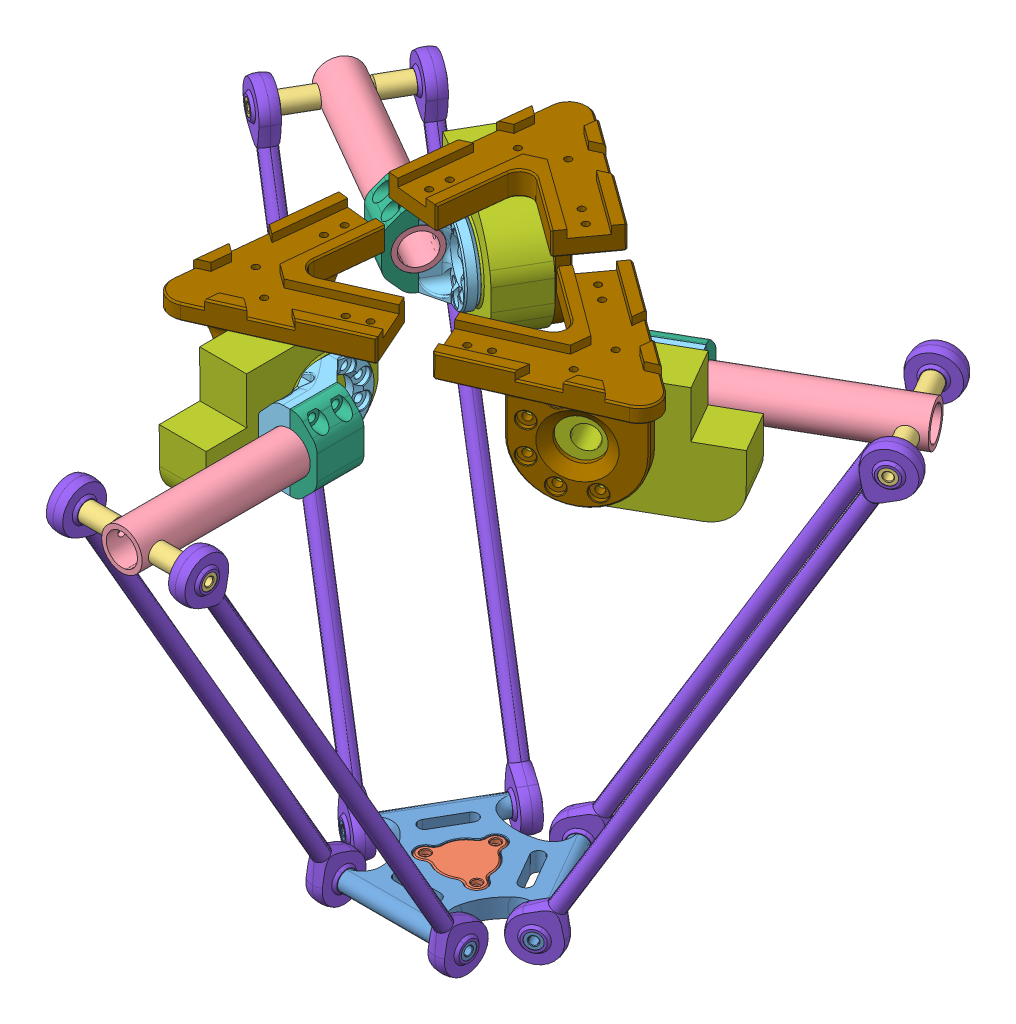
SolidWorks assembly delta-unattached-static, configuration Default. Lengths in mm.
Overall size (445.41 366.22 385.74).
29 component instances, 9 part files, 69 mates.
Components (placement in the parent):
- flange-star-1: flange-star [Default] at origin size (130.67 31.15 114.22)
- calibration-pin-1: calibration-pin [Default] at (0 12 0) x (0.5 0 -0.866025) z (-0.866025 0 -0.5) size (44.16 32 40.5)
- connection-tap-joint-2: connection-tap-joint [Default] at (-45.9 293.4704 210.0514) x (0 -1 0) z (0 0 1) size (12 32.9 12)
- connection-tap-joint-3: connection-tap-joint [Default] at (45.9 293.4704 210.0514) x (0 0.993683 -0.11222) z (0 0.11222 0.993683) size (12 32.9 12)
- proximal-link-1: proximal-link [Default] at (0 293.4704 82.5514) x (0 -1 0) z (0 0 1) size (26 26 137.5)
- revolute-joint-1: revolute-joint [Default] at (-20 293.4704 70.0514) x (0 0 1) z (0 1 0) size (66.5 20.7 48.61)
- joint-clamp-1: joint-clamp [Default] at (8.55 293.4829 82.5514) x (0 -1 0) z (0 0 1) size (48 17.3 30)
- connection-tap-joint-4: connection-tap-joint [Default] at (-158.9598 293.4704 -144.7763) x (-0.224339 0.965866 -0.129522) z (0.836464 0.259044 0.482933) size (12 32.9 12)
- connection-tap-joint-5: connection-tap-joint [Default] at (-204.8598 293.4704 -65.2751) x (0.186633 -0.976503 0.107752) z (0.845676 0.215505 0.488251) size (12 32.9 12)
- proximal-link-3: proximal-link [Default] at (-71.4916 293.4704 -41.2757) x (0 -1 0) z (-0.866025 0 -0.5) size (26 26 137.5)
- revolute-joint-2: revolute-joint [Default] at (-50.6663 293.4704 -52.3462) x (-0.866025 0 -0.5) z (0 1 0) size (66.5 20.7 48.61)
- joint-clamp-2: joint-clamp [Default] at (-75.7666 293.4829 -33.8712) x (0 -1 0) z (-0.866025 0 -0.5) size (48 17.3 30)
- connection-tap-joint-6: connection-tap-joint [Default] at (204.8598 293.4704 -65.2751) x (0.224339 0.965866 -0.129522) z (-0.836464 0.259044 0.482933) size (12 32.9 12)
- connection-tap-joint-7: connection-tap-joint [Default] at (158.9598 293.4704 -144.7763) x (-0.424943 0.871339 0.245341) z (0.754601 0.490682 -0.435669) size (12 32.9 12)
- proximal-link-5: proximal-link [Default] at (71.4916 293.4704 -41.2757) x (0 -1 0) z (0.866025 0 -0.5) size (26 26 137.5)
- revolute-joint-3: revolute-joint [Default] at (70.6663 293.4704 -17.7052) x (0.866025 0 -0.5) z (0 1 0) size (66.5 20.7 48.61)
- joint-clamp-3: joint-clamp [Default] at (67.2166 293.4829 -48.6802) x (0 -1 0) z (0.866025 0 -0.5) size (48 17.3 30)
- Hebi-X5-1_draft-3: Hebi-X5-1_draft [Default] at (-51.1 293.3938 90.0512) x (0 -0.999993 -0.003829) z (0 -0.003829 0.999993) size (73 31.1 110)
- KDGM_10_A_ER_J_2.stp-1: KDGM_10_A_ER_J_2.stp [Default] at (39.1 149.7122 127.048) x (0 0.500021 -0.866014) z (0 0.866014 0.500021) size (30 14 362)
- KDGM_10_A_ER_J_2.stp-2: KDGM_10_A_ER_J_2.stp [Default] at (-39.1 149.7122 127.048) x (0 0.500021 -0.866014) z (0 0.866014 0.500021) size (30 14 362)
- KDGM_10_A_ER_J_2.stp-3: KDGM_10_A_ER_J_2.stp [Default] at (-129.5768 149.7122 -29.6624) x (-0.74999 -0.500021 -0.433007) z (-0.43303 0.866014 -0.25001) size (30 14 362)
- KDGM_10_A_ER_J_2.stp-4: KDGM_10_A_ER_J_2.stp [Default] at (-90.4768 149.7122 -97.3856) x (-0.74999 -0.500021 -0.433007) z (-0.43303 0.866014 -0.25001) size (30 14 362)
- KDGM_10_A_ER_J_2.stp-5: KDGM_10_A_ER_J_2.stp [Default] at (90.4768 149.7122 -97.3856) x (-0.74999 0.500021 0.433007) z (0.43303 0.866014 -0.25001) size (30 14 362)
- KDGM_10_A_ER_J_2.stp-6: KDGM_10_A_ER_J_2.stp [Default] at (129.5768 149.7122 -29.6624) x (-0.74999 0.500021 0.433007) z (0.43303 0.866014 -0.25001) size (30 14 362)
- Hebi-X5-1_draft-4: Hebi-X5-1_draft [Default] at (103.5367 293.3938 -0.7717) x (-0.003316 -0.999993 0.001915) z (0.866019 -0.003829 -0.499996) size (73 31.1 110)
- Hebi-X5-1_draft-5: Hebi-X5-1_draft [Default] at (-52.4367 293.3938 -89.2795) x (0.003316 -0.999993 0.001915) z (-0.866019 -0.003829 -0.499996) size (73 31.1 110)
- base-mount-1: base-mount [Default] at (-51.1 293.4781 68.0514) x (0 -0.003829 0.999993) z (0 -0.999993 -0.003829) size (108.14 103.78 86.5)
- base-mount-2: base-mount [Default] at (84.4842 293.4781 10.2282) x (0.866019 -0.003829 -0.499996) z (-0.003316 -0.999993 0.001915) size (108.14 103.78 86.5)
- base-mount-3: base-mount [Default] at (-33.3842 293.4781 -78.2796) x (-0.866019 -0.003829 -0.499996) z (0.003316 -0.999993 0.001915) size (108.14 103.78 86.5)
Mates (geometry in assembly coordinates):
- Coincident1: coincident: plane of flange-star-1 through (-5.419 7 -18.5519) normal (0 1 0); plane of calibration-pin-1 through (10.4372 7 -0.081) normal (0 -1 0)
- Concentric1: concentric: cylinder of flange-star-1 through (0 21.5681 -19) axis (0 -1 0) radius 1.625; cylinder of calibration-pin-1 through (0 7 -19) axis (0 1 0) radius 1.625
- Concentric7: concentric: cylinder of connection-tap-joint-2 through (-13 293.4704 210.0514) axis (-1 0 0) radius 2.625; cylinder of proximal-link-1 through (150 293.4704 210.0514) axis (-1 0 0) radius 2.65
- Tangent4: tangent: plane of connection-tap-joint-2 through (-13 293.4704 210.0514) normal (1 0 0); cylinder of proximal-link-1 through (0 293.4704 220.0514) axis (0 0 -1) radius 13
- Concentric9: concentric: cylinder of connection-tap-joint-3 through (13 293.4704 210.0514) axis (1 0 0) radius 2.625; cylinder of proximal-link-1 through (150 293.4704 210.0514) axis (-1 0 0) radius 2.65
- Concentric10: concentric: cylinder of proximal-link-1 through (-13 293.4704 92.5514) axis (1 0 0) radius 2.5; cylinder of revolute-joint-1 through (-10.41 293.4704 92.5514) axis (-1 0 0) radius 2.45
- Concentric11: concentric: cylinder of proximal-link-1 through (0 293.4704 220.0514) axis (0 0 -1) radius 13; cylinder of revolute-joint-1 through (0 293.4704 112.5514) axis (0 0 -1) radius 13.125
- Concentric12: concentric: cylinder of revolute-joint-1 through (-20.6235 312.0454 105.0514) axis (1 0 0) radius 2.625; cylinder of joint-clamp-1 through (17.3 312.0454 105.0514) axis (-1 0 0) radius 2.625
- Concentric13: concentric: cylinder of revolute-joint-1 through (-20.6235 312.0454 90.0514) axis (1 0 0) radius 2.625; cylinder of joint-clamp-1 through (17.3 312.0454 90.0514) axis (-1 0 0) radius 2.625
- Coincident8: coincident: plane of revolute-joint-1 through (0 293.4704 70.0514) normal (1 0 0); plane of joint-clamp-1 through (0 293.4829 82.5514) normal (-1 0 0)
- Concentric14: concentric: cylinder of flange-star-1 through (-16.4545 21.5681 9.5) axis (0 -1 0) radius 1.625; cylinder of calibration-pin-1 through (-16.4545 7 9.5) axis (0 1 0) radius 1.625
- Concentric21: concentric: cylinder of connection-tap-joint-4 through (-175.4098 293.4704 -116.284) axis (0.5 0 -0.866025) radius 2.625; cylinder of proximal-link-3 through (-256.9098 293.4704 24.8781) axis (0.5 0 -0.866025) radius 2.65
- Tangent6: tangent: plane of connection-tap-joint-4 through (-175.4098 293.4704 -116.284) normal (-0.5 0 0.866025); cylinder of proximal-link-3 through (-190.5701 293.4704 -110.0257) axis (0.866025 0 0.5) radius 13
- Concentric22: concentric: cylinder of connection-tap-joint-5 through (-188.4098 293.4704 -93.7674) axis (-0.5 0 0.866025) radius 2.625; cylinder of proximal-link-3 through (-256.9098 293.4704 24.8781) axis (0.5 0 -0.866025) radius 2.65
- Concentric23: concentric: cylinder of proximal-link-3 through (-82.3121 293.4704 -62.534) axis (-0.5 0 0.866025) radius 2.5; cylinder of revolute-joint-2 through (-83.6071 293.4704 -60.291) axis (0.5 0 -0.866025) radius 2.45
- Concentric24: concentric: cylinder of proximal-link-3 through (-190.5701 293.4704 -110.0257) axis (0.866025 0 0.5) radius 13; cylinder of revolute-joint-2 through (-97.4724 293.4704 -56.2757) axis (0.866025 0 0.5) radius 13.125
- Concentric26: concentric: cylinder of revolute-joint-2 through (-67.6751 312.0454 -62.8862) axis (-0.5 0 0.866025) radius 2.625; cylinder of joint-clamp-2 through (-86.6368 312.0454 -30.0435) axis (0.5 0 -0.866025) radius 2.625
- Concentric27: concentric: cylinder of revolute-joint-2 through (-80.6654 312.0454 -70.3862) axis (-0.5 0 0.866025) radius 2.625; cylinder of joint-clamp-2 through (-99.6272 312.0454 -37.5435) axis (0.5 0 -0.866025) radius 2.625
- Coincident13: coincident: plane of revolute-joint-2 through (-60.6663 293.4704 -35.0257) normal (-0.5 0 0.866025); plane of joint-clamp-2 through (-71.4916 293.4829 -41.2757) normal (0.5 0 -0.866025)
- Concentric34: concentric: cylinder of connection-tap-joint-6 through (188.4098 293.4704 -93.7674) axis (0.5 0 0.866025) radius 2.625; cylinder of proximal-link-5 through (106.9098 293.4704 -234.9295) axis (0.5 0 0.866025) radius 2.65
- Tangent8: tangent: plane of connection-tap-joint-6 through (188.4098 293.4704 -93.7674) normal (-0.5 0 -0.866025); cylinder of proximal-link-5 through (190.5701 293.4704 -110.0257) axis (-0.866025 0 0.5) radius 13
- Concentric35: concentric: cylinder of connection-tap-joint-7 through (175.4098 293.4704 -116.284) axis (-0.5 0 -0.866025) radius 2.625; cylinder of proximal-link-5 through (106.9098 293.4704 -234.9295) axis (0.5 0 0.866025) radius 2.65
- Concentric36: concentric: cylinder of proximal-link-5 through (95.3121 293.4704 -40.0174) axis (-0.5 0 -0.866025) radius 2.5; cylinder of revolute-joint-3 through (94.0171 293.4704 -42.2604) axis (0.5 0 0.866025) radius 2.45
- Concentric37: concentric: cylinder of proximal-link-5 through (190.5701 293.4704 -110.0257) axis (-0.866025 0 0.5) radius 13; cylinder of revolute-joint-3 through (97.4724 293.4704 -56.2757) axis (-0.866025 0 0.5) radius 13.125
- Concentric38: concentric: cylinder of revolute-joint-3 through (88.2985 312.0454 -27.1652) axis (-0.5 0 -0.866025) radius 2.625; cylinder of joint-clamp-3 through (69.3368 312.0454 -60.0079) axis (0.5 0 0.866025) radius 2.625
- Concentric39: concentric: cylinder of revolute-joint-3 through (101.2889 312.0454 -34.6652) axis (-0.5 0 -0.866025) radius 2.625; cylinder of joint-clamp-3 through (82.3272 312.0454 -67.5079) axis (0.5 0 0.866025) radius 2.625
- Coincident19: coincident: plane of revolute-joint-3 through (60.6663 293.4704 -35.0257) normal (-0.5 0 -0.866025); plane of joint-clamp-3 through (71.4916 293.4829 -41.2757) normal (0.5 0 0.866025)
- Coincident22: coincident: plane of revolute-joint-1 through (-20 293.4704 70.0514) normal (-1 0 0); plane of Hebi-X5-1_draft-3 through (-20 293.4704 70.0514) normal (1 0 0)
- Concentric47: concentric: cylinder of flange-star-1 through (45.9 5.9539 44.0446) axis (-1 0 0) radius 4.9; cylinder of KDGM_10_A_ER_J_2.stp-1 through (39.1 5.9539 44.0446) axis (1 0 0) radius 5
- Coincident23: coincident: plane of flange-star-1 through (32.1 6 44) normal (1 0 0); plane of KDGM_10_A_ER_J_2.stp-1 through (32.1 5.9539 44.0446) normal (-1 0 0)
- Concentric48: concentric: cylinder of flange-star-1 through (-45.9 5.9539 44.0446) axis (1 0 0) radius 4.9; cylinder of KDGM_10_A_ER_J_2.stp-2 through (-39.1 5.9539 44.0446) axis (1 0 0) radius 5
- Coincident24: coincident: plane of flange-star-1 through (-32.1 6 44) normal (-1 0 0); plane of KDGM_10_A_ER_J_2.stp-2 through (-32.1 5.9539 44.0446) normal (1 0 0)
- Concentric49: concentric: cylinder of connection-tap-joint-2 through (-32.1 293.4704 210.0514) axis (-1 0 0) radius 4.9; cylinder of KDGM_10_A_ER_J_2.stp-2 through (-39.1 293.4704 210.0514) axis (-1 0 0) radius 5
- Tangent9: tangent: plane of connection-tap-joint-3 through (13 293.4704 210.0514) normal (-1 0 0); cylinder of proximal-link-1 through (0 293.4704 220.0514) axis (0 0 -1) radius 13
- Concentric50: concentric: cylinder of connection-tap-joint-3 through (32.1 293.4704 210.0514) axis (1 0 0) radius 4.9; cylinder of KDGM_10_A_ER_J_2.stp-1 through (39.1 293.4704 210.0514) axis (-1 0 0) radius 5
- Coincident25: coincident: plane of connection-tap-joint-2 through (-32.1 293.4704 210.0514) normal (-1 0 0); plane of KDGM_10_A_ER_J_2.stp-2 through (-32.1 293.4704 210.0514) normal (1 0 0)
- Concentric51: concentric: cylinder of connection-tap-joint-5 through (-197.9598 293.4704 -77.2263) axis (-0.5 0 0.866025) radius 4.9; cylinder of KDGM_10_A_ER_J_2.stp-3 through (-201.4598 293.4704 -71.1641) axis (-0.5 0 0.866025) radius 5
- Tangent10: tangent: plane of connection-tap-joint-5 through (-188.4098 293.4704 -93.7674) normal (0.5 0 -0.866025); cylinder of proximal-link-3 through (-190.5701 293.4704 -110.0257) axis (0.866025 0 0.5) radius 13
- Coincident26: coincident: plane of connection-tap-joint-5 through (-197.9598 293.4704 -77.2263) normal (-0.5 0 0.866025); plane of KDGM_10_A_ER_J_2.stp-3 through (-197.9598 293.4704 -77.2263) normal (0.5 0 -0.866025)
- Concentric52: concentric: cylinder of flange-star-1 through (-61.0937 5.9539 17.7283) axis (0.5 0 -0.866025) radius 4.9; cylinder of KDGM_10_A_ER_J_2.stp-3 through (-57.6937 5.9539 11.8393) axis (0.5 0 -0.866025) radius 5
- Coincident27: coincident: plane of flange-star-1 through (-54.1551 6 5.7994) normal (-0.5 0 0.866025); plane of KDGM_10_A_ER_J_2.stp-3 through (-54.1937 5.9539 5.7771) normal (0.5 0 -0.866025)
- Concentric53: concentric: cylinder of flange-star-1 through (-15.1937 5.9539 -61.7729) axis (-0.5 0 0.866025) radius 4.9; cylinder of KDGM_10_A_ER_J_2.stp-4 through (-18.5937 5.9539 -55.8839) axis (0.5 0 -0.866025) radius 5
- Concentric54: concentric: cylinder of connection-tap-joint-4 through (-165.8598 293.4704 -132.8251) axis (0.5 0 -0.866025) radius 4.9; cylinder of KDGM_10_A_ER_J_2.stp-4 through (-162.3598 293.4704 -138.8873) axis (-0.5 0 0.866025) radius 5
- Coincident28: coincident: plane of flange-star-1 through (-22.0551 6 -49.7994) normal (0.5 0 -0.866025); plane of KDGM_10_A_ER_J_2.stp-4 through (-22.0937 5.9539 -49.8217) normal (-0.5 0 0.866025)
- Concentric55: concentric: cylinder of connection-tap-joint-7 through (165.8598 293.4704 -132.8251) axis (-0.5 0 -0.866025) radius 4.9; cylinder of KDGM_10_A_ER_J_2.stp-5 through (162.3598 293.4704 -138.8873) axis (0.5 0 0.866025) radius 5
- Concentric56: concentric: cylinder of flange-star-1 through (15.1937 5.9539 -61.7729) axis (0.5 0 0.866025) radius 4.9; cylinder of KDGM_10_A_ER_J_2.stp-5 through (18.5937 5.9539 -55.8839) axis (-0.5 0 -0.866025) radius 5
- Coincident29: coincident: plane of flange-star-1 through (22.0551 6 -49.7994) normal (-0.5 0 -0.866025); plane of KDGM_10_A_ER_J_2.stp-5 through (22.0937 5.9539 -49.8217) normal (0.5 0 0.866025)
- Tangent11: tangent: plane of connection-tap-joint-7 through (175.4098 293.4704 -116.284) normal (0.5 0 0.866025); cylinder of proximal-link-5 through (190.5701 293.4704 -110.0257) axis (-0.866025 0 0.5) radius 13
- Concentric57: concentric: cylinder of connection-tap-joint-6 through (197.9598 293.4704 -77.2263) axis (0.5 0 0.866025) radius 4.9; cylinder of KDGM_10_A_ER_J_2.stp-6 through (201.4598 293.4704 -71.1641) axis (0.5 0 0.866025) radius 5
- Concentric58: concentric: cylinder of flange-star-1 through (61.0937 5.9539 17.7283) axis (-0.5 0 -0.866025) radius 4.9; cylinder of KDGM_10_A_ER_J_2.stp-6 through (57.6937 5.9539 11.8393) axis (-0.5 0 -0.866025) radius 5
- Coincident30: coincident: plane of flange-star-1 through (54.1551 6 5.7994) normal (0.5 0 0.866025); plane of KDGM_10_A_ER_J_2.stp-6 through (54.1937 5.9539 5.7771) normal (-0.5 0 -0.866025)
- Coincident31: coincident: plane of connection-tap-joint-6 through (197.9598 293.4704 -77.2263) normal (0.5 0 0.866025); plane of KDGM_10_A_ER_J_2.stp-6 through (197.9598 293.4704 -77.2263) normal (-0.5 0 -0.866025)
- Coincident47: coincident: plane of proximal-link-5 through (71.4916 293.4704 -41.2757) normal (0 -1 0); plane of assembly through (0 293.4704 0) normal (0 1 0)
- Coincident48: coincident: plane of proximal-link-1 through (0 293.4704 82.5514) normal (0 -1 0); plane of assembly through (0 293.4704 0) normal (0 1 0)
- Coincident49: coincident: plane of proximal-link-3 through (-71.4916 293.4704 -41.2757) normal (0 -1 0); plane of assembly through (0 293.4704 0) normal (0 1 0)
- Concentric59: concentric: cylinder of revolute-joint-1 through (-20.6235 277.277 76.6864) axis (1 0 0) radius 2.625; cylinder of Hebi-X5-1_draft-3 through (-20 277.277 76.6864) axis (-1 0 0) radius 2.625
- Concentric60: concentric: cylinder of revolute-joint-1 through (-20.6235 277.3283 63.2926) axis (1 0 0) radius 2.625; cylinder of Hebi-X5-1_draft-3 through (-20 277.3283 63.2926) axis (-1 0 0) radius 2.625
- Concentric61: concentric: cylinder of revolute-joint-3 through (76.7241 277.277 -20.4827) axis (-0.5 0 -0.866025) radius 2.625; cylinder of Hebi-X5-1_draft-4 through (76.4124 277.277 -21.0227) axis (0.5 0 0.866025) radius 2.625
- Concentric62: concentric: cylinder of revolute-joint-3 through (65.1247 277.3283 -13.7858) axis (-0.5 0 -0.866025) radius 2.625; cylinder of Hebi-X5-1_draft-4 through (64.813 277.3283 -14.3258) axis (0.5 0 0.866025) radius 2.625
- Coincident50: coincident: plane of revolute-joint-3 through (70.6663 293.4704 -17.7052) normal (0.5 0 0.866025); plane of Hebi-X5-1_draft-4 through (70.6663 293.4704 -17.7052) normal (-0.5 0 -0.866025)
- Concentric63: concentric: cylinder of revolute-joint-2 through (-56.1006 277.277 -56.2037) axis (-0.5 0 0.866025) radius 2.625; cylinder of Hebi-X5-1_draft-5 through (-56.4124 277.277 -55.6637) axis (0.5 0 -0.866025) radius 2.625
- Concentric64: concentric: cylinder of revolute-joint-2 through (-44.5012 277.3283 -49.5067) axis (-0.5 0 0.866025) radius 2.625; cylinder of Hebi-X5-1_draft-5 through (-44.813 277.3283 -48.9668) axis (0.5 0 -0.866025) radius 2.625
- Coincident51: coincident: plane of revolute-joint-2 through (-50.6663 293.4704 -52.3462) normal (0.5 0 -0.866025); plane of Hebi-X5-1_draft-5 through (-50.6663 293.4704 -52.3462) normal (-0.5 0 0.866025)
- Coincident52: coincident: plane of Hebi-X5-1_draft-3 through (-51.1 293.3938 90.0512) normal (-1 0 0); plane of base-mount-1 through (-51.1 293.4781 68.0514) normal (1 0 0)
- Coincident53: coincident: plane of Hebi-X5-1_draft-4 through (103.5367 293.3938 -0.7717) normal (0.5 0 0.866025); plane of base-mount-2 through (86.2163 293.4704 9.2282) normal (-0.5 0 -0.866025)
- Coincident54: coincident: plane of Hebi-X5-1_draft-5 through (-52.4367 293.3938 -89.2795) normal (0.5 0 -0.866025); plane of base-mount-3 through (-35.1163 293.4704 -79.2796) normal (-0.5 0 0.866025)
- Concentric65: concentric: cylinder of Hebi-X5-1_draft-3 through (-46.1 269.2342 77.9849) axis (-1 0 0) radius 2.625; cylinder of base-mount-1 through (-51.1 269.2342 77.9849) axis (-1 0 0) radius 2.625
- Concentric66: concentric: cylinder of Hebi-X5-1_draft-5 through (-44.4869 269.2342 -78.9162) axis (0.5 0 -0.866025) radius 2.625; cylinder of base-mount-3 through (-41.9869 269.2342 -83.2464) axis (0.5 0 -0.866025) radius 2.625
- Concentric67: concentric: cylinder of Hebi-X5-1_draft-4 through (90.5869 269.2342 0.9313) axis (0.5 0 0.866025) radius 2.625; cylinder of base-mount-2 through (93.0869 269.2342 5.2614) axis (0.5 0 0.866025) radius 2.625
